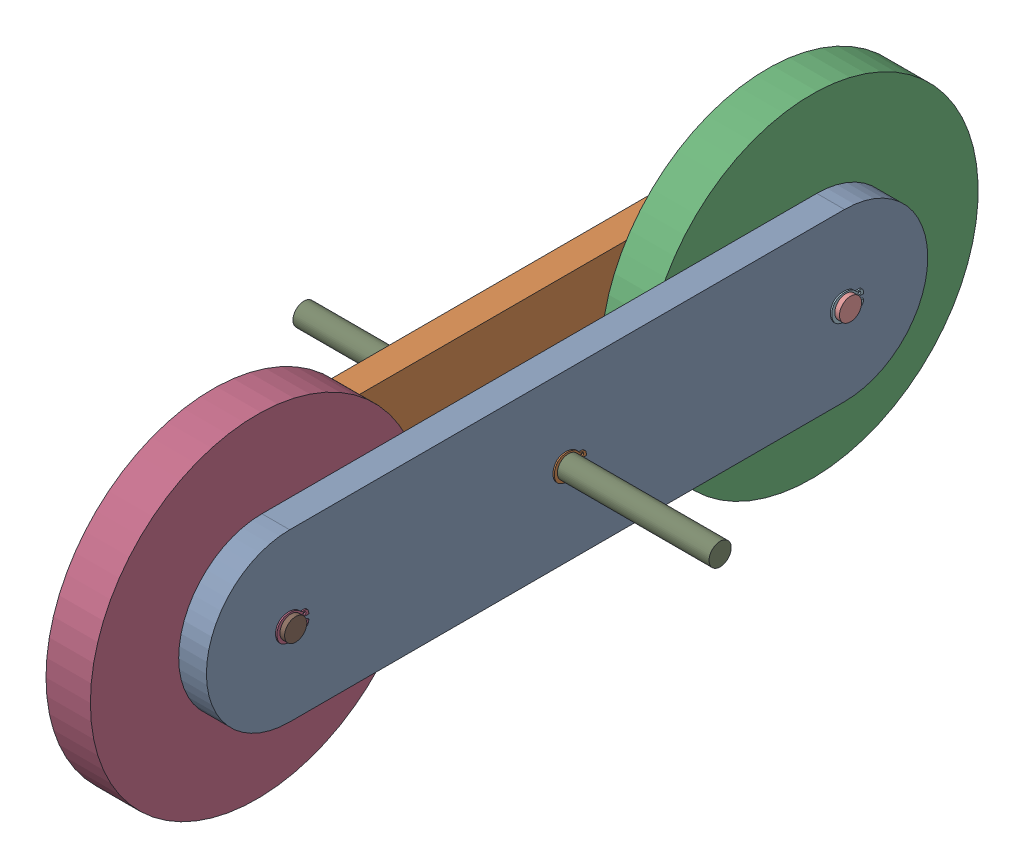
SolidWorks assembly Balancer-Dx, configuration Default. Lengths in mm.
Overall size (75 60.41 160.21).
17 component instances, 6 part files, 33 mates.
Components (placement in the parent):
- Balancer-lateral-Dx-1: Balancer-lateral-Dx [Default] at (57.5274 93.4575 -114.567) size (5 30 130)
- Balancer-lateral-Dx-2: Balancer-lateral-Dx [Default] at (42.6994 93.4575 -114.567) size (5 30 130)
- Balancer-Wheel-Dx-1: Balancer-Wheel-Dx [Default] at (48.6134 93.4575 -164.567) x (1 0 0) z (0 0.006923 0.999976) size (8 60 60)
- Balancer-Wheel-Dx-2: Balancer-Wheel-Dx [Default] at (48.6134 93.4575 -64.567) size (8 60 60)
- Bearing-4mm-Dx-1: Bearing-4mm-Dx [Default] at (57.5275 93.4575 -164.567) size (3.17 9.12 9.12)
- Bearing-4mm-Dx-2: Bearing-4mm-Dx [Default] at (47.6994 93.4575 -164.567) x (-1 0 0) z (0 0 -1) size (3.17 9.12 9.12)
- Bearing-4mm-Dx-3: Bearing-4mm-Dx [Default] at (57.5275 93.4575 -64.567) size (3.17 9.12 9.12)
- Bearing-4mm-Dx-4: Bearing-4mm-Dx [Default] at (47.6994 93.4575 -64.567) x (-1 0 0) z (0 0 -1) size (3.17 9.12 9.12)
- Shaft-4mm-Dx-1: Shaft-4mm-Dx [Default] at (15.1134 93.4575 -114.567) x (1 0 0) z (0 -0.936019 -0.351949) size (75 4 4)
- Balancer-Shaft-4mm-Dx-1: Balancer-Shaft-4mm-Dx [Default] at (41.6134 93.4575 -164.567) size (22 4 4)
- Balancer-Shaft-4mm-Dx-2: Balancer-Shaft-4mm-Dx [Default] at (41.6134 93.4575 -64.567) size (22 4 4)
- msh_4-Dx-1: msh_4-Dx [Default] at (62.6524 93.4575 -164.567) x (0 1 0) z (0 0 1) size (4.59 0.25 5.77)
- msh_4-Dx-2: msh_4-Dx [Default] at (42.5744 93.4575 -164.567) x (0 0.77366 -0.633601) z (0 0.633601 0.77366) size (4.59 0.25 5.77)
- msh_4-Dx-3: msh_4-Dx [Default] at (62.6524 93.4575 -114.567) x (0 0.995776 -0.091812) z (0 0.091812 0.995776) size (4.59 0.25 5.77)
- msh_4-Dx-4: msh_4-Dx [Default] at (42.5744 93.4575 -114.567) x (0 1 0) z (0 0 1) size (4.59 0.25 5.77)
- msh_4-Dx-5: msh_4-Dx [Default] at (62.6524 93.4575 -64.567) x (0 1 0) z (0 0 1) size (4.59 0.25 5.77)
- msh_4-Dx-6: msh_4-Dx [Default] at (42.5744 93.4575 -64.567) x (0 1 0) z (0 0 1) size (4.59 0.25 5.77)
Mates (geometry in assembly coordinates):
- Coincidente1: coincident anti-aligned: plane of Balancer-Wheel-Dx-1 through (56.6134 93.4575 -164.567) normal (1 0 0); plane of Bearing-4mm-Dx-1 through (56.6134 98.017 -164.567) normal (-1 0 0)
- Concentrico1: concentric aligned: circle of Balancer-Wheel-Dx-1; circle of Bearing-4mm-Dx-1
- Coincidente2: coincident anti-aligned: plane of Balancer-Wheel-Dx-1 through (48.6134 93.4575 -164.567) normal (-1 0 0); plane of Bearing-4mm-Dx-2 through (48.6134 98.017 -164.567) normal (1 0 0)
- Concentrico2: concentric anti-aligned: circle of Balancer-Wheel-Dx-1; circle of Bearing-4mm-Dx-2
- Coincidente3: coincident anti-aligned: plane of Balancer-lateral-Dx-1 through (57.5274 93.4575 -164.567) normal (-1 0 0); plane of Bearing-4mm-Dx-1 through (57.5274 96.7909 -164.567) normal (1 0 0)
- Concentrico3: concentric aligned: circle of Balancer-lateral-Dx-1; circle of Bearing-4mm-Dx-1
- Coincidente4: coincident anti-aligned: plane of Balancer-lateral-Dx-2 through (47.6994 93.4575 -164.567) normal (1 0 0); plane of Bearing-4mm-Dx-2 through (47.6994 96.7909 -164.567) normal (-1 0 0)
- Concentrico4: concentric aligned: circle of Balancer-lateral-Dx-1; circle of Balancer-lateral-Dx-2
- Coincidente5: coincident anti-aligned: plane of Balancer-Wheel-Dx-2 through (56.6134 93.4575 -64.567) normal (1 0 0); plane of Bearing-4mm-Dx-3 through (56.6134 98.017 -64.567) normal (-1 0 0)
- Concentrico5: concentric aligned: circle of Balancer-Wheel-Dx-2; circle of Bearing-4mm-Dx-3
- Coincidente6: coincident anti-aligned: plane of Balancer-Wheel-Dx-2 through (48.6134 93.4575 -64.567) normal (-1 0 0); plane of Bearing-4mm-Dx-4 through (48.6134 98.017 -64.567) normal (1 0 0)
- Concentrico6: concentric anti-aligned: circle of Balancer-Wheel-Dx-2; circle of Bearing-4mm-Dx-4
- Coincidente7: coincident anti-aligned: plane of Balancer-lateral-Dx-2 through (47.6994 93.4575 -164.567) normal (1 0 0); plane of Bearing-4mm-Dx-4 through (47.6994 96.7909 -64.567) normal (-1 0 0)
- Concentrico7: concentric aligned: circle of Balancer-lateral-Dx-1; circle of Bearing-4mm-Dx-3
- Concentrico8: concentric aligned: circle of Balancer-lateral-Dx-1; circle of Balancer-lateral-Dx-2
- Concentrico9: concentric aligned: circle of Balancer-lateral-Dx-2; circle of Shaft-4mm-Dx-1
- Larghezza1: width anti-aligned: plane of Shaft-4mm-Dx-1 through (90.1134 93.4575 -114.567) normal (1 0 0); plane of Shaft-4mm-Dx-1 through (15.1134 93.4575 -114.567) normal (-1 0 0); plane of Balancer-lateral-Dx-2 through (42.6994 93.4575 -164.567) normal (-1 0 0); plane of Balancer-lateral-Dx-1 through (62.5274 93.4575 -164.567) normal (1 0 0)
- Concentrico10: concentric aligned: circle of Balancer-lateral-Dx-1; circle of Balancer-Shaft-4mm-Dx-1
- Larghezza2: width anti-aligned: plane of Balancer-Shaft-4mm-Dx-1 through (41.6134 93.4575 -164.567) normal (-1 0 0); plane of Balancer-Shaft-4mm-Dx-1 through (63.6134 93.4575 -164.567) normal (1 0 0); plane of Balancer-lateral-Dx-1 through (62.5274 93.4575 -164.567) normal (1 0 0); plane of Balancer-lateral-Dx-2 through (42.6994 93.4575 -164.567) normal (-1 0 0)
- Concentrico11: concentric aligned: circle of Balancer-lateral-Dx-1; circle of Balancer-Shaft-4mm-Dx-2
- Larghezza3: width aligned: plane of Balancer-Shaft-4mm-Dx-2 through (63.6134 93.4575 -64.567) normal (1 0 0); plane of Balancer-Shaft-4mm-Dx-2 through (41.6134 93.4575 -64.567) normal (-1 0 0); plane of Balancer-lateral-Dx-1 through (62.5274 93.4575 -164.567) normal (1 0 0); plane of Balancer-lateral-Dx-2 through (42.6994 93.4575 -164.567) normal (-1 0 0)
- Concentrico12: concentric aligned: circle of Balancer-Shaft-4mm-Dx-1; circle of msh_4-Dx-1
- Coincidente8: coincident anti-aligned: plane of Balancer-lateral-Dx-1 through (62.5274 93.4575 -164.567) normal (1 0 0); plane of msh_4-Dx-1 through (62.5274 93.0075 -167.7352) normal (-1 0 0)
- Concentrico13: concentric aligned: circle of Balancer-Shaft-4mm-Dx-1; circle of msh_4-Dx-2
- Coincidente9: coincident anti-aligned: plane of Balancer-lateral-Dx-2 through (42.6994 93.4575 -164.567) normal (-1 0 0); plane of msh_4-Dx-2 through (42.6994 91.102 -166.733) normal (1 0 0)
- Concentrico14: concentric aligned: circle of Balancer-lateral-Dx-1; circle of msh_4-Dx-3
- Coincidente10: coincident anti-aligned: plane of Balancer-lateral-Dx-1 through (62.5274 93.4575 -164.567) normal (1 0 0); plane of msh_4-Dx-3 through (62.5274 92.7186 -117.6805) normal (-1 0 0)
- Coincidente11: coincident anti-aligned: plane of Balancer-lateral-Dx-2 through (42.6994 93.4575 -164.567) normal (-1 0 0); plane of msh_4-Dx-4 through (42.6994 93.0075 -117.7352) normal (1 0 0)
- Concentrico15: concentric aligned: circle of Balancer-lateral-Dx-2; circle of msh_4-Dx-4
- Coincidente12: coincident anti-aligned: plane of Balancer-lateral-Dx-1 through (62.5274 93.4575 -164.567) normal (1 0 0); plane of msh_4-Dx-5 through (62.5274 93.0075 -67.7352) normal (-1 0 0)
- Concentrico16: concentric aligned: circle of Balancer-lateral-Dx-1; circle of msh_4-Dx-5
- Coincidente13: coincident anti-aligned: plane of Balancer-lateral-Dx-2 through (42.6994 93.4575 -164.567) normal (-1 0 0); plane of msh_4-Dx-6 through (42.6994 93.0075 -67.7352) normal (1 0 0)
- Concentrico17: concentric aligned: circle of Balancer-lateral-Dx-2; circle of msh_4-Dx-6
